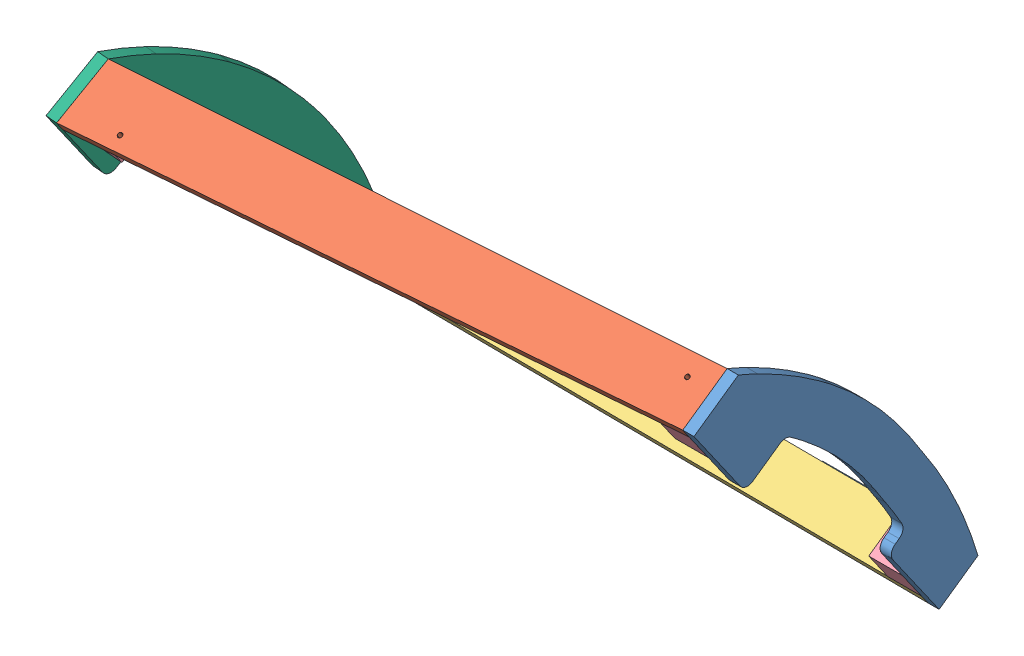
SolidWorks assembly Back hatch assembly, configuration Default. Lengths in mm.
Overall size (180.54 86.57 90.7).
11 component instances, 6 part files, 50 mates.
Components (placement in the parent):
- back fuel hatch front edge (51in)-1: back fuel hatch front edge (51in) [Default] at (-26.9875 -0.6998 0.9994) size (4.69 86.09 81.38)
- back fuel hatch top edge-2: back fuel hatch top edge [Default] at (-26.9875 85.7771 61.5511) x (1 0 0) z (0 0.819152 0.573576) size (169.82 24.98 3.17)
- back fuel hatch bottom edge-2: back fuel hatch bottom edge [Default] at (-26.9875 1.2508 2.3652) x (-1 0 0) z (0 -0.819152 -0.573576) size (168.29 14.06 3.17)
- short balsa hatch corner-1: short balsa hatch corner [Default] at (-28.575 151.6923 -38.121) x (0 0.573576 -0.819152) z (-1 0 0) size (12.7 9.53 9.53)
- short balsa hatch corner-2: short balsa hatch corner [Default] at (-28.575 79.6467 -104.0602) x (0 -0.573576 0.819152) z (-1 0 0) size (12.7 9.53 9.53)
- short balsa hatch corner-3: short balsa hatch corner [Default] at (-197.8105 147.6452 -32.3411) x (-0.066233 -0.572317 0.817353) z (0.997804 -0.03799 0.054255) size (12.7 9.53 9.53)
- short balsa hatch corner-4: short balsa hatch corner [Default] at (-196.4438 80.1298 -104.7502) x (-0.066233 -0.572317 0.817353) z (0 0.819152 0.573576) size (12.7 9.53 9.53)
- Hinge assembly-1: Hinge assembly [Default] at (-2116.9732 81.2407 -112.5641) x (1 0 0) z (0 -0.573576 0.819152) size (19.05 1.59 13.39) (flexible)
  - Hinge-1: Hinge [Top] at (2047.1232 -0.3969 13.3874) size (19.05 0.79 13.39)
  - Hinge-2: Hinge [Top] at (2066.1732 0.3969 13.3874) x (-1 0 0) z (0 0 1) size (19.05 0.79 13.39)
- back fuel hatch back edge (58in)-1: back fuel hatch back edge (58in) [Default] at (-206.4617 6.0128 -1.6679) x (0.997804 -0.03799 0.054255) z (-0.054255 0.001032 0.998527) size (4.89 80.77 89.9)
Mates (geometry in assembly coordinates):
- Coincident1: coordinate: point of back fuel hatch front edge (51in)-1
- Distance1: distance = 165.1 mm aligned: plane of back fuel hatch front edge (51in)-1 through (-25.4 -0.6998 0.9994) normal (1 0 0); plane of back fuel hatch front edge (51in)-2 through (166.6875 0 0) normal (1 0 0)
- Coincident3: coincident aligned: plane of back fuel hatch front edge (51in)-2 through (165.1 0 0) normal (0 0 1)
- Coincident4: coincident aligned: plane of back fuel hatch front edge (51in)-2 through (165.1 0 0) normal (0 1 0)
- InPlace1: in place: plane of ? through (162.8775 83.2258 58.2754) normal (0 0.819152 0.573576); plane of ? through (0 83.2258 58.2754) normal (0 0.819152 0.573576); moOrthogonalPlaneRef_w of ? through (162.8775 83.2258 58.2754) normal (0 0.819152 0.573576); plane of ? through (0 83.2258 58.2754) normal (0 0.573576 -0.819152); plane of ? through (162.8775 83.2258 58.2754) normal (0 0.819152 0.573576); plane of ? through (0 83.2258 58.2754) normal (1 0 0); plane of ? through (162.8775 83.2258 58.2754) normal (0 0.819152 0.573576); unknown of ?
- Coincident5: coincident aligned: plane of ?; plane of ?
- Coincident6: coincident aligned: moOrthogonalPlaneRef_w of back fuel hatch front edge (51in)-2 through (165.1 83.2258 58.2754) normal (0 0.573576 -0.819152); plane of Part3^Assem1-1 through (165.1 83.2258 58.2754) normal (0 0.573576 -0.819152)
- Coincident7: coincident anti-aligned: moOrthogonalPlaneRef_w of back fuel hatch front edge (51in)-2 through (165.1 83.2258 58.2754) normal (-1 0 0); plane of Part3^Assem1-1 through (165.1 83.2258 58.2754) normal (1 0 0)
- Distance2: distance = 171.45 mm: plane of back fuel hatch front edge (51in)-1 through (-25.4 43.1912 22.3393) normal (1 0 0); plane of back fuel hatch back edge (58in) - Copy-1 through (-204.9399 48.3132 18.5375) normal (0.997804 -0.017075 0.063994)
- Coincident12: coincident aligned: unknown of back fuel hatch back edge (58in) - Copy-1
- Coincident13: coincident aligned: unknown of back fuel hatch back edge (58in) - Copy-1
- InPlace3: in place: plane of assembly through (-2.2225 83.2258 58.2754) normal (0 0.819152 0.573576); plane of ? through (0 83.2258 58.2754) normal (0 0.819152 0.573576); plane of assembly through (-2.2225 83.2258 58.2754) normal (0 0.819152 0.573576); plane of ? through (0 83.2258 58.2754) normal (0 0.573576 -0.819152); plane of assembly through (-2.2225 83.2258 58.2754) normal (0 0.819152 0.573576); plane of ? through (0 83.2258 58.2754) normal (1 0 0); unknown of back fuel hatch front edge (51in)-1; unknown of back fuel hatch top edge-2
- Coincident14: coincident aligned: plane of assembly through (-26.9875 85.7771 61.5511) normal (0 0.819152 0.573576)
- Coincident15: coincident aligned: moOrthogonalPlaneRef_w of back fuel hatch front edge (51in)-1 through (-26.9875 85.7771 61.5511) normal (0 0.573576 -0.819152); plane of back fuel hatch top edge-2 through (-26.9875 85.7771 61.5511) normal (0 0.573576 -0.819152)
- Coincident16: coincident anti-aligned: moOrthogonalPlaneRef_w of back fuel hatch front edge (51in)-1 through (-26.9875 85.7771 61.5511) normal (-1 0 0); plane of back fuel hatch top edge-2 through (-26.9875 85.7771 61.5511) normal (1 0 0)
- InPlace4: in place: plane of assembly through (-2.2225 5.2016 3.6422) normal (0 -0.819152 -0.573576); plane of ? through (0 5.2016 3.6422) normal (0 -0.819152 -0.573576); plane of assembly through (-2.2225 5.2016 3.6422) normal (0 -0.819152 -0.573576); plane of ? through (0 5.2016 3.6422) normal (0 0.573576 -0.819152); plane of assembly through (-2.2225 5.2016 3.6422) normal (0 -0.819152 -0.573576); plane of ? through (0 5.2016 3.6422) normal (-1 0 0); unknown of back fuel hatch front edge (51in)-1; unknown of back fuel hatch bottom edge-2
- Coincident17: coincident aligned: plane of back fuel hatch front edge (51in)-1; plane of back fuel hatch bottom edge-2
- Coincident18: coincident aligned: moOrthogonalPlaneRef_w of back fuel hatch front edge (51in)-1 through (-26.9875 1.2508 2.3652) normal (0 0.573576 -0.819152); plane of back fuel hatch bottom edge-2 through (-26.9875 1.2508 2.3652) normal (0 0.573576 -0.819152)
- Coincident19: coincident anti-aligned: moOrthogonalPlaneRef_w of back fuel hatch front edge (51in)-1 through (-26.9875 1.2508 2.3652) normal (1 0 0); plane of back fuel hatch bottom edge-2 through (-26.9875 1.2508 2.3652) normal (-1 0 0)
- Coincident20: coincident anti-aligned: plane of back fuel hatch top edge-2 through (-26.9875 83.1763 59.73) normal (0 -0.819152 -0.573576); plane of short balsa hatch corner-1 through (-28.575 155.3345 -43.3226) normal (0 0.819152 0.573576)
- Coincident21: coincident anti-aligned: plane of back fuel hatch front edge (51in)-1 through (-28.575 -0.6998 0.9994) normal (-1 0 0); plane of short balsa hatch corner-1 through (-28.575 155.3345 -43.3226) normal (1 0 0)
- Coincident22: coincident aligned: plane of back fuel hatch front edge (51in)-1; plane of short balsa hatch corner-1
- Coincident23: coincident anti-aligned: plane of back fuel hatch bottom edge-2 through (-26.9875 3.8517 4.1863) normal (0 0.819152 0.573576); plane of short balsa hatch corner-2 through (-28.575 76.0045 -98.8586) normal (0 -0.819152 -0.573576)
- Coincident24: coincident anti-aligned: plane of back fuel hatch front edge (51in)-1 through (-28.575 -0.6998 0.9994) normal (-1 0 0); plane of short balsa hatch corner-2 through (-28.575 76.0045 -98.8586) normal (1 0 0)
- Coincident25: coincident aligned: plane of back fuel hatch front edge (51in)-1; plane of short balsa hatch corner-2
- Coincident26: coincident anti-aligned: plane of back fuel hatch top edge-2 through (-26.9875 83.1763 59.73) normal (0 -0.819152 -0.573576); plane of short balsa hatch corner-3 through (-198.2311 144.0109 -27.1509) normal (0 0.819152 0.573576)
- Coincident27: coincident anti-aligned: plane of back fuel hatch back edge (58in) - Copy-1 through (-204.8777 48.5875 17.5095) normal (0.997804 -0.017075 0.063994); plane of short balsa hatch corner-3 through (-198.2311 144.0109 -27.1509) normal (-0.997804 0.03799 -0.054255)
- Distance3: distance = 2.54 mm aligned: plane of short balsa hatch corner-3 through (-198.2311 144.0109 -27.1509) normal (-0.066233 -0.572317 0.817353); plane of back fuel hatch back edge (58in) - Copy-1 through (-201.5679 73.8008 -76.9837) normal (-0.066233 -0.25724 0.964075)
- Coincident29: coincident anti-aligned: plane of back fuel hatch back edge (58in) - Copy-1 through (-204.8777 48.5875 17.5095) normal (0.997804 -0.017075 0.063994); plane of short balsa hatch corner-4 through (-196.8644 76.4956 -99.56) normal (-0.997804 0.03799 -0.054255)
- Coincident30: coincident anti-aligned: plane of back fuel hatch bottom edge-2 through (-26.9875 3.8517 4.1863) normal (0 0.819152 0.573576); plane of short balsa hatch corner-4 through (-196.8644 76.4956 -99.56) normal (0 -0.819152 -0.573576)
- Distance4: distance = 80.5213 mm: line of Hinge assembly-1/Hinge-2 through (-69.85 80.5213 -112.2287) axis (1 0 0)
- Distance5: distance = 112.2287 mm: line of Hinge assembly-1/Hinge-2 through (-69.85 80.5213 -112.2287) axis (1 0 0)
- Angle1: planar angle = 0.610865 rad anti-aligned: plane of Hinge assembly-1/Hinge-2 through (-50.8 73.2369 -101.8255) normal (0 -0.819152 -0.573576)
- Distance7: distance = 50.8 mm aligned: plane of Hinge assembly-1/Hinge-2 through (-50.8 73.2369 -101.8255) normal (1 0 0)
- Coincident35: coincident anti-aligned: plane of back fuel hatch bottom edge-2 through (-26.9875 1.2508 2.3652) normal (0 -0.819152 -0.573576); plane of Hinge assembly-1/Hinge-1 through (-69.85 73.8871 -101.3702) normal (0 0.819152 0.573576)
- Coincident37: coincident: line of back fuel hatch bottom edge-2 through (-28.575 81.1258 -111.7081) axis (-0.999994 0.002059 -0.002941); point of Hinge assembly-1/Hinge-1
- Distance8: distance = 25.4 mm aligned: plane of Hinge assembly-1/Hinge-1 through (-50.8 73.8871 -101.3702) normal (1 0 0); plane of back fuel hatch front edge (51in)-1 through (-25.4 -0.6998 0.9994) normal (1 0 0)
- Coincident39: coincident aligned: plane of back fuel hatch back edge (58in) - Copy-1 through (-208.6794 146.8182 43.4588) normal (0 0.966197 0.257806); plane of back fuel hatch top edge-2 through (-26.9875 85.7771 61.5511) normal (0 0.819152 0.573576)
- Coincident45: coincident: line of back fuel hatch back edge (58in) - Copy-1 through (-196.8644 78.1763 -99.5399) axis (0 0.966197 0.257806); point of back fuel hatch bottom edge-2
- Coincident46: coincident aligned: plane of back fuel hatch back edge (58in) - Copy-1 through (-200.0324 79.7643 -99.3338) normal (-0.066233 -0.25724 0.964075); plane of short balsa hatch corner-4 through (-196.8644 76.4956 -99.56) normal (-0.066233 -0.572317 0.817353)
- Coincident47: coincident anti-aligned: plane of back fuel hatch back edge (58in) - Copy-1 through (-204.8777 48.5875 17.5095) normal (0.997804 -0.017075 0.063994); plane of back fuel hatch top edge-2 through (-204.4893 89.9344 50.0785) normal (-0.997804 0.03799 -0.054255)
- Coincident48: coincident anti-aligned: plane of back fuel hatch bottom edge-2 through (-26.9875 3.8517 4.1863) normal (0 0.819152 0.573576); plane of short balsa hatch corner-4 through (-196.8644 76.4956 -99.56) normal (0 -0.819152 -0.573576)
- Coincident49: coincident aligned: plane of back fuel hatch bottom edge-2 through (-204.4893 10.6097 -5.4653) normal (-0.997804 0.03799 -0.054255); plane of short balsa hatch corner-4 through (-196.8644 76.4956 -99.56) normal (-0.997804 0.03799 -0.054255)
- Coincident50: coincident anti-aligned: plane of back fuel hatch top edge-2 through (-26.9875 83.1763 59.73) normal (0 -0.819152 -0.573576); plane of short balsa hatch corner-3 through (-198.2311 144.0109 -27.1509) normal (0 0.819152 0.573576)
- Coincident51: coincident aligned: plane of back fuel hatch top edge-2 through (-204.4893 89.9344 50.0785) normal (-0.997804 0.03799 -0.054255); plane of short balsa hatch corner-3 through (-198.2311 144.0109 -27.1509) normal (-0.997804 0.03799 -0.054255)
- Distance9: distance = 2.54 mm: point of back fuel hatch top edge-2; plane of short balsa hatch corner-3 through (-198.2311 144.0109 -27.1509) normal (-0.066233 -0.572317 0.817353)
- Distance10: distance = 0 mm: plane of short balsa hatch corner-4 through (-196.8644 76.4956 -99.56) normal (-0.066233 -0.572317 0.817353); point of back fuel hatch bottom edge-2
- Coincident52: coincident anti-aligned: plane of back fuel hatch top edge-2 through (-204.4893 89.9344 50.0785) normal (-0.997804 0.03799 -0.054255); plane of back fuel hatch back edge (58in)-1 through (-204.8777 5.9525 -1.5818) normal (0.997804 -0.03799 0.054255)
- Coincident53: coincident aligned: plane of back fuel hatch top edge-2 through (-26.9875 85.7771 61.5511) normal (0 0.819152 0.573576); plane of back fuel hatch back edge (58in)-1 through (-208.6794 89.3231 56.4869) normal (0 0.819152 0.573576)
- Coincident54: coincident: plane of back fuel hatch top edge-2 through (-33.3556 147.8996 -32.7044) normal (0.056344 -0.572665 0.817851); point of back fuel hatch back edge (58in)-1
